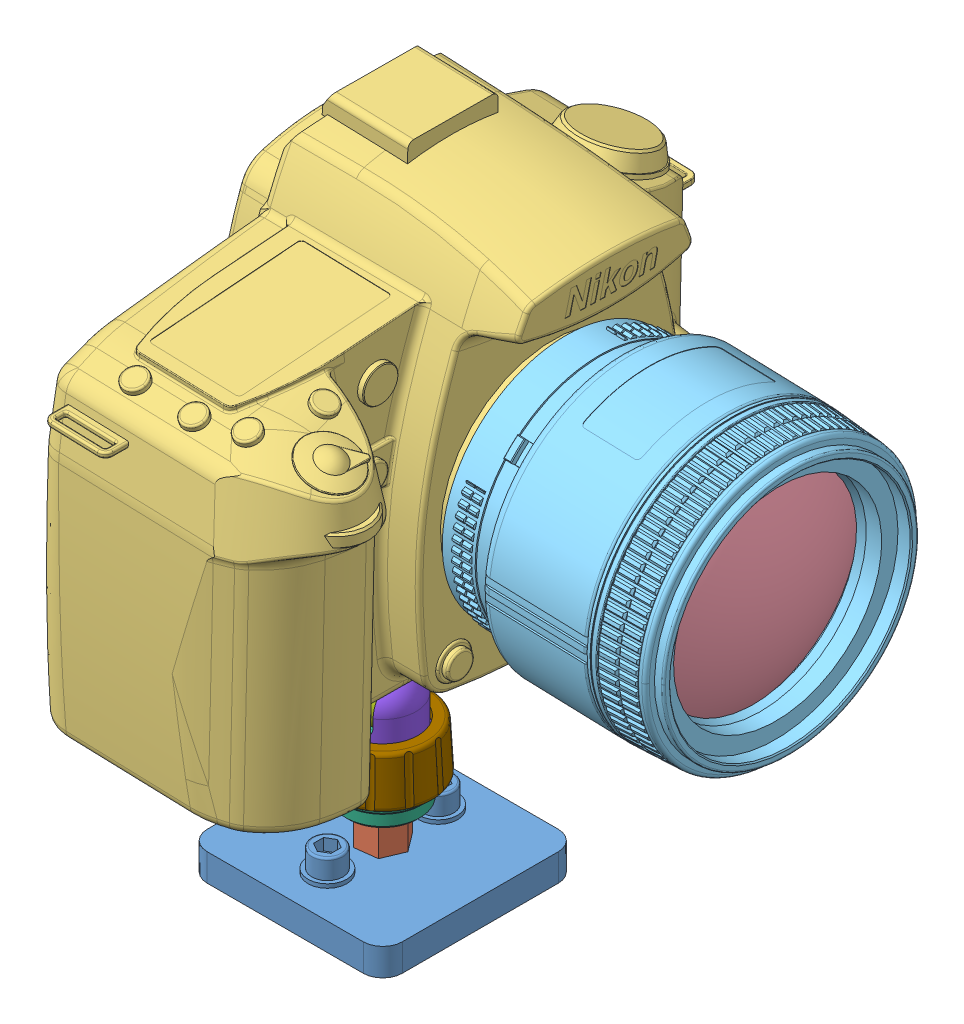
SolidWorks assembly 20.026_00_KAMERA SLIDER MONTAJ, configuration Default. Lengths in mm.
Overall size (129.18 166.23 141.1).
14 component instances, 11 part files, 0 mates.
Components (placement in the parent):
- Mini V Gantry Set-1: Mini V Gantry Set [Default] at (-152.4196 23.1382 944.8746) x (0 0 1) z (-1 0 0) size (50 25 50)
  - Mini V Gantry Plate-1: Mini V Gantry Plate [Default] at origin size (50 13 50)
  - 20.026_L-001-1: 20.026_L-001 [Default] at (0 24 0) x (-0.124096 0 -0.99227) z (0 -1 0) size (11.55 10 25)
- 35755_Nikon_D90_Camera_NURBS-1: 35755_Nikon_D90_Camera_NURBS [Default] at (-151.7739 123.7139 932.5206) x (0.00665 0.000715 -0.999978) z (0.999681 -0.024381 0.00663) size (140.17 109.03 125.63)
  - D90_BODY-1: D90_BODY [Default] at origin size (140.17 109.03 80.13)
  - LENS-1: LENS [Default] at (0 0 79.2905) x (0 0 1) z (0 1 0) size (22.02 56.32 59.86)
  - LENS_85MM-1: LENS_85MM [Default] at (0 0 33.3) x (0 0 1) z (0 1 0) size (63.3 71.35 80.29)
- ball joint tripod adapter-1: ball joint tripod adapter [Default] at (-152.4196 39.1382 944.8746) x (-0.984396 0 0.175965) z (-0.175965 0 -0.984396) size (28.07 46.61 28.09)
  - main base-1: main base [Default] at origin size (21.4 19.7 21.4)
  - ball joint bolt-1: ball joint bolt [Default] at (0 23.35 0) x (0.99388 0.024332 0.107748) z (-0.107738 -0.001697 0.994178) size (12.8 29.5 12.8)
  - bolt house-1: bolt house [Default] at (0 14.1 0) size (19.5 14.8 19.5)
  - fastner-1: fastner [Default] at (0 6 0) size (25.73 12.8 25.74)
  - friction rubber-1: friction rubber [Default] at (-0.3802 38.9454 -0.0146) x (0.99388 0.024332 0.107748) z (-0.107738 -0.001697 0.994178) size (20 3 20)
  - camera base nut-1: camera base nut [Default] at (-0.368 38.4455 -0.0141) x (0.99388 0.024332 0.107748) z (-0.107738 -0.001697 0.994178) size (25.36 5 25.5)
